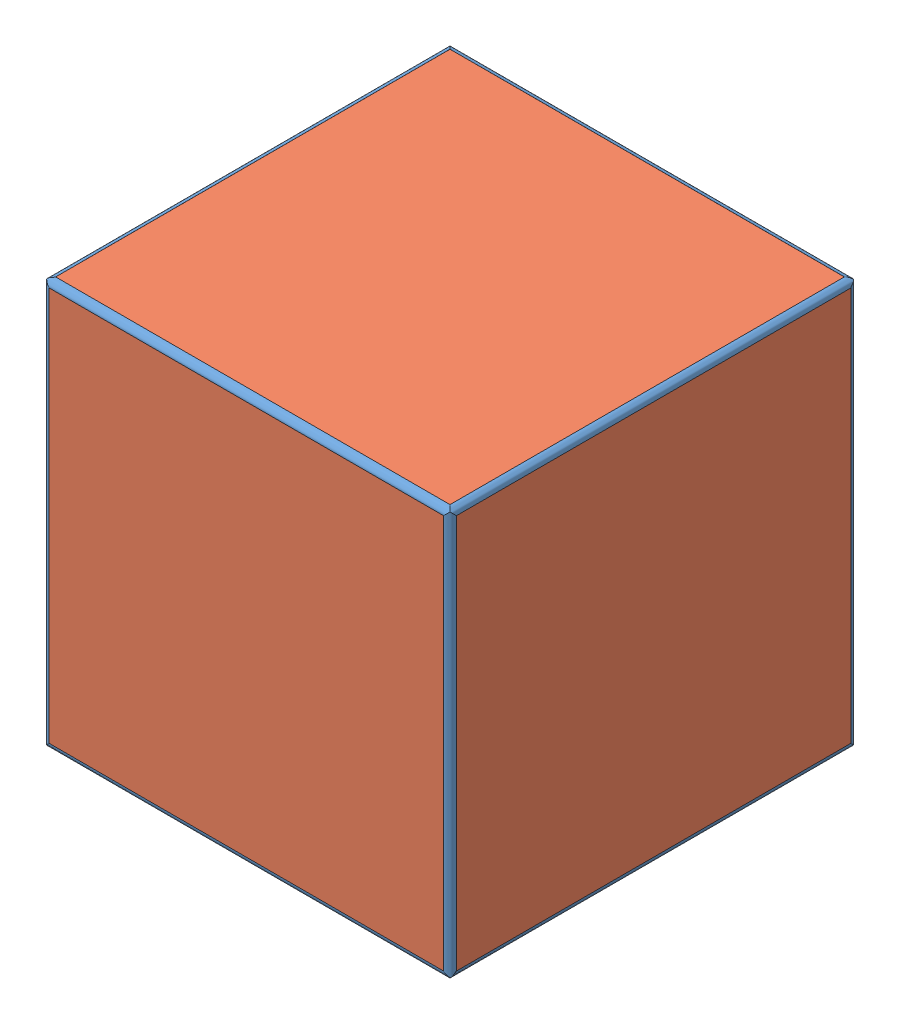
SolidWorks assembly Cube Assem, configuration Default. Lengths in mm.
Overall size (257.76 257.76 257.76).
19 component instances, 3 part files, 3 mates.
Components (placement in the parent):
- Cube-1: Cube [Default] at origin size (254 254 254) (hidden)
- Joiner_For_Cube-1: Joiner_For_Cube [Default] at (0 127 127) x (0 1 0) z (1 0 0) size (12.28 12.36 254.85)
- Joiner_For_Cube-2: Joiner_For_Cube [Default] at (-127 127 0) x (0 1 0) z (0 0 1) size (12.28 12.36 254.85)
- Joiner_For_Cube-7: Joiner_For_Cube [Default] at (-127 0 127) x (-1 0 0) z (0 1 0) size (12.28 12.36 254.85)
- Joiner_For_Cube-8: Joiner_For_Cube [Default] at (0 -127 127) x (0 -1 0) z (-1 0 0) size (12.28 12.36 254.85)
- Joiner_For_Cube-9: Joiner_For_Cube [Default] at (127 0 127) x (1 0 0) z (0 -1 0) size (12.28 12.36 254.85)
- Joiner_For_Cube-10: Joiner_For_Cube [Default] at (-127 -127 0) x (-1 0 0) z (0 0 1) size (12.28 12.36 254.85)
- Joiner_For_Cube-11: Joiner_For_Cube [Default] at (127 -127 0) x (0 -1 0) z (0 0 1) size (12.28 12.36 254.85)
- Joiner_For_Cube-12: Joiner_For_Cube [Default] at (127 127 0) size (12.28 12.36 254.85)
- Joiner_For_Cube-13: Joiner_For_Cube [Default] at (0 127 -127) x (0 1 0) z (-1 0 0) size (12.28 12.36 254.85)
- Joiner_For_Cube-14: Joiner_For_Cube [Default] at (-127 0 -127) x (-1 0 0) z (0 -1 0) size (12.28 12.36 254.85)
- Joiner_For_Cube-15: Joiner_For_Cube [Default] at (0 -127 -127) x (0 -1 0) z (1 0 0) size (12.28 12.36 254.85)
- Joiner_For_Cube-16: Joiner_For_Cube [Default] at (127 0 -127) x (1 0 0) z (0 1 0) size (12.28 12.36 254.85)
- Face^Cube Assem-1: Face^Cube Assem [Default] at origin size (248.92 248.92 3) (virtual)
- Face^Cube Assem-2: Face^Cube Assem [Default] x (0 0 1) z (-1 0 0) size (248.92 248.92 3) (virtual)
- Face^Cube Assem-3: Face^Cube Assem [Default] x (-1 0 0) z (0 0 -1) size (248.92 248.92 3) (virtual)
- Face^Cube Assem-4: Face^Cube Assem [Default] x (0 0 -1) z (1 0 0) size (248.92 248.92 3) (virtual)
- Face^Cube Assem-5: Face^Cube Assem [Default] x (1 0 0) z (0 1 0) size (248.92 248.92 3) (virtual)
- Face^Cube Assem-6: Face^Cube Assem [Default] x (1 0 0) z (0 -1 0) size (248.92 248.92 3) (virtual)
Mates (geometry in assembly coordinates):
- Coincident1: coincident anti-aligned: line of Cube-1 through (127 127 127) axis (-1 0 0); line of Joiner_Base-1 through (-88.99 127 127) axis (1 0 0)
- Coincident2: coincident: plane of Joiner_Base-1 through (0 127 127) normal (1 0 0)
- Coincident3: coincident: plane of Joiner_Base-1 through (0 127 127) normal (0 -0.707107 0.707107)
